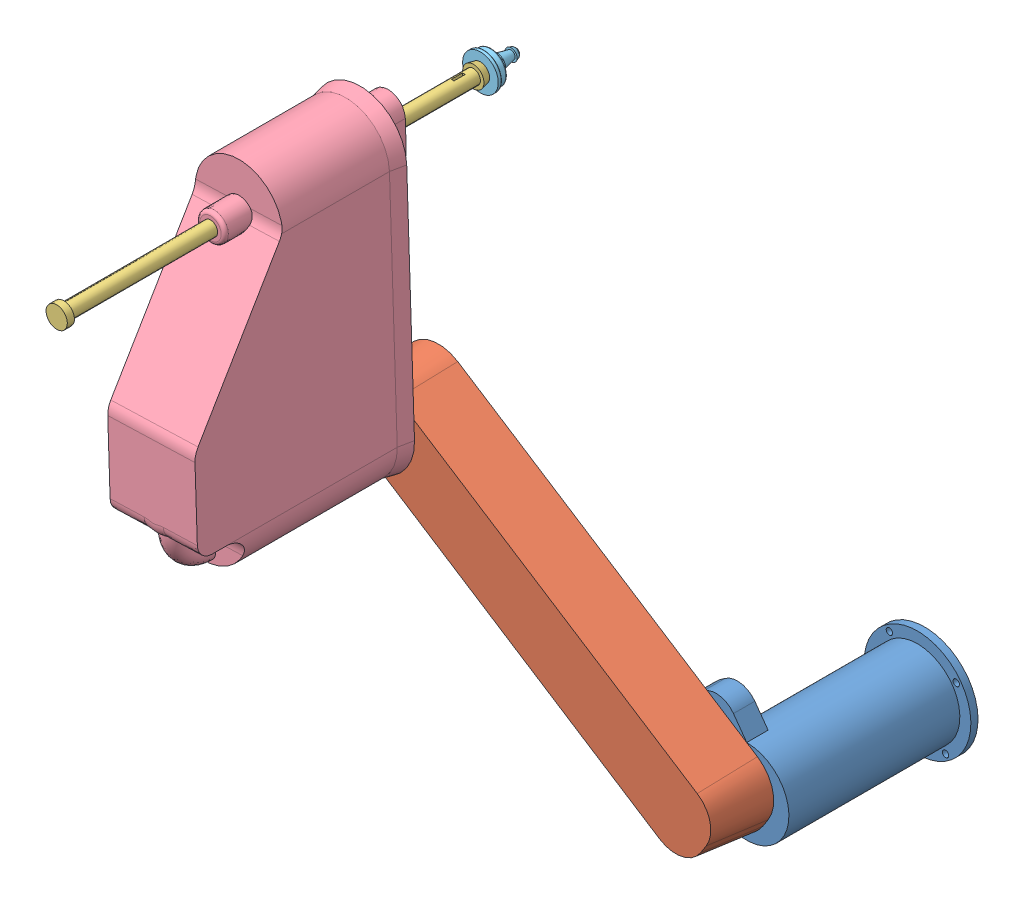
SolidWorks assembly Scara_robot, configuration Default. Lengths in mm.
Overall size (624.99 783.27 766.08).
5 component instances, 5 part files, 10 mates.
Components (placement in the parent):
- Part1-1: Part1 [Default] x (-0.584543 0.811363 0) z (0 0 1) size (185 150 250)
- Part2-1: Part2 [Default] at (-441.8136 283.5944 255) x (0.84155 -0.54018 0) z (0 0 1) size (600 114 115)
- Part3-1: Part3 [Default] at (-452.5577 608.4167 166.0824) x (-0.033059 0.999453 0) z (0 0 1) size (30 30 600)
- Part4-1: Part4 [Default] at (-441.8136 283.5944 340) x (0.033059 -0.999453 0) z (0 0 1) size (461.06 131.06 340)
- Part5-2: Part5 [Default] at (-452.5577 608.4167 166.0824) x (-0.265837 -0.964018 0) z (0 0 -1) size (50 50 50)
Mates (geometry in assembly coordinates):
- Concentric2: concentric aligned: cylinder of Part1-1 through (0 0 220) axis (0 0 1) radius 10; cylinder of Part2-1 through (0 0 220) axis (0 0 1) radius 10
- Coincident6: coincident anti-aligned: plane of Part1-1 through (0 0 220) normal (0 0 1); plane of Part2-1 through (0 0 220) normal (0 0 -1)
- Concentric3: concentric aligned: cylinder of Part2-1 through (-441.8136 283.5944 305) axis (0 0 1) radius 10; cylinder of Part4-1 through (-441.8136 283.5944 305) axis (0 0 1) radius 10
- Coincident7: coincident anti-aligned: plane of Part2-1 through (-441.8136 283.5944 305) normal (0 0 1); plane of Part4-1 through (-441.8136 283.5944 305) normal (0 0 -1)
- Concentric4: concentric aligned: cylinder of Part3-1 through (-452.5577 608.4167 756.0824) axis (0 0 -1) radius 10; cylinder of Part4-1 through (-452.5577 608.4167 578.2843) axis (0 0 -1) radius 10
- Coincident12: coincident: point of Part1-1
- Parallel2: parallel anti-aligned: plane of Part1-1 through (0 0 0) normal (0 0 -1)
- Parallel3: parallel aligned: plane of Part3-1 through (-450.5588 608.4829 166.0824) normal (-0.999453 -0.033059 0); plane of Part4-1 through (-477.2598 627.0454 300) normal (-0.999453 -0.033059 0)
- Coincident14: coincident anti-aligned: plane of Part3-1 through (-452.5577 608.4167 166.0824) normal (0 0 -1); plane of Part5-2 through (-452.5577 608.4167 166.0824) normal (0 0 1)
- Concentric5: concentric anti-aligned: cylinder of Part3-1 through (-452.5577 608.4167 756.0824) axis (0 0 -1) radius 10; cylinder of Part5-2 through (-452.5577 608.4167 166.0824) axis (0 0 1) radius 10
